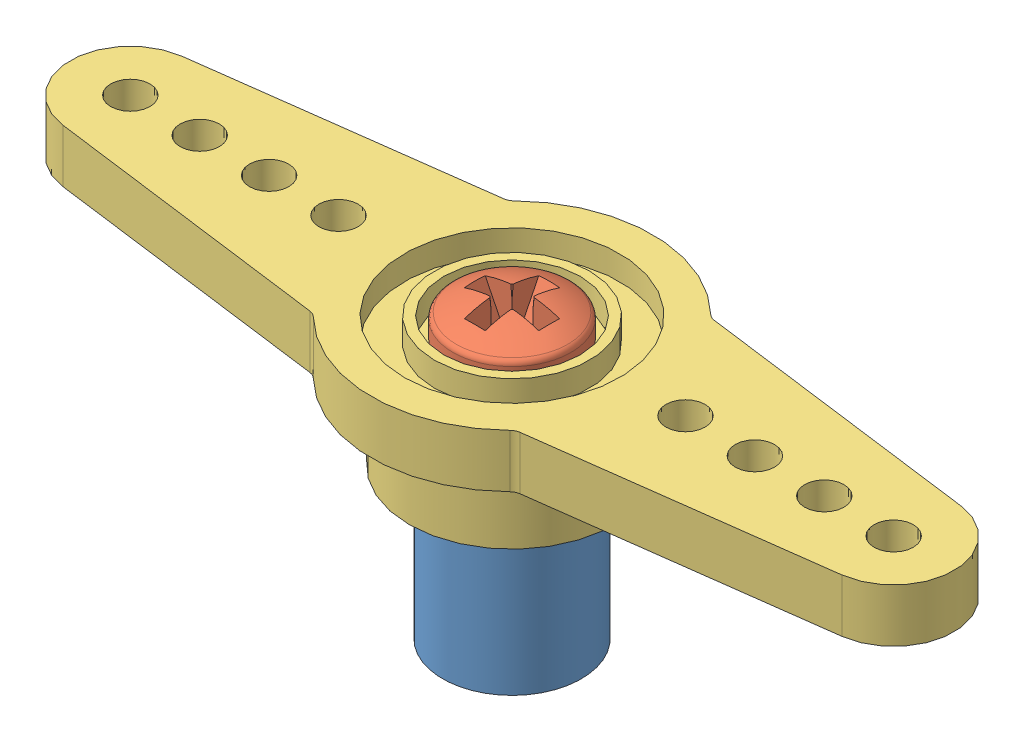
SolidWorks assembly FS5109M_Ensemble arbre, configuration 2S. Lengths in mm.
Overall size (55.74 14.3 36.6).
7 component instances, 7 part files, 23 mates.
Components (placement in the parent):
- FS5109M_arbre-1: FS5109M_arbre [Défaut] at origin size (6 10 6)
- FS5109M_vis arbre M3 x 6-1: FS5109M_vis arbre M3 x 6 [vis arbre M3 x 6] at (0 47.05 0) x (0 -1 0) z (0 0 1) size (7.75 5.1 5.1)
- FS5109M_palo 2S-1: FS5109M_palo 2S [Défaut] at (0 44.2 0) size (38.2 5.6 12.15)
- FS5109M_palo 2B-1: FS5109M_palo 2B [Défaut] at (0 44.2 0) size (55.74 7.8 13.34) (hidden)
- FS5109M_palo C-1: FS5109M_palo C [Défaut] at (0 44.2 0) size (20.9 5.6 20.9) (hidden)
- FS5109M_palo 4-1: FS5109M_palo 4 [Défaut] at (0 44.2 0) size (36.6 5.6 36.6) (hidden)
- FS5109M_palo 6-1: FS5109M_palo 6 [Défaut] at (0 44.2 0) size (31.74 5.6 28.12) (hidden)
Mates (geometry in assembly coordinates):
- Coïncidente1: coordinate: point of FS5109M_arbre-1; point of assembly
- Coaxiale1: concentric aligned: cylinder of FS5109M_arbre-1 through (0 44.2 0) axis (0 1 0) radius 1.25; cylinder of FS5109M_vis arbre M3 x 6-1 through (0 72.45 0) axis (0 1 0) radius 1.5
- Coïncidente2: coincident aligned: line of FS5109M_arbre-1 through (0 0 0) axis (0 1 0); line of FS5109M_palo 2S-1 through (0 44.2 0) axis (0 1 0)
- Coïncidente3: coincident aligned: plane of FS5109M_arbre-1 through (-2.5 44.2 0) normal (0 1 0); plane of FS5109M_palo 2S-1 through (0 44.2 0) normal (0 1 0)
- Coïncidente4: coincident anti-aligned: plane of FS5109M_vis arbre M3 x 6-1 through (1.5 45.25 0) normal (0 -1 0); plane of FS5109M_palo 2S-1 through (0 45.25 0) normal (0 1 0)
- Coïncidente5: coincident aligned: plane of FS5109M_arbre-1 through (0 0 0) normal (0 0 1); plane of FS5109M_palo 2S-1 through (0 44.2 0) normal (0 0 1)
- Coïncidente6: coincident aligned: line of FS5109M_arbre-1 through (0 0 0) axis (0 1 0); line of FS5109M_palo 2B-1 through (0 44.2 0) axis (0 1 0)
- Coïncidente7: coincident aligned: plane of FS5109M_arbre-1 through (0 0 0) normal (0 0 1); plane of FS5109M_palo 2B-1 through (0 44.2 0) normal (0 0 1)
- Coïncidente8: coincident aligned: plane of FS5109M_arbre-1 through (-2.5 44.2 0) normal (0 1 0); plane of FS5109M_palo 2B-1 through (0 44.2 0) normal (0 1 0)
- Coïncidente9: coincident anti-aligned: plane of FS5109M_vis arbre M3 x 6-1 through (0.732 45.2 1.3093) normal (0 -1 0); plane of FS5109M_palo 2B-1 through (0 45.2 0) normal (0 1 0)
- Coïncidente10: coincident anti-aligned: plane of FS5109M_vis arbre M3 x 6-1 through (0.732 45.25 1.3093) normal (0 -1 0); plane of FS5109M_palo C-1 through (0 45.25 0) normal (0 1 0)
- Coïncidente11: coincident aligned: plane of FS5109M_arbre-1 through (-2.5 44.2 0) normal (0 1 0); plane of FS5109M_palo C-1 through (0 44.2 0) normal (0 1 0)
- Coïncidente12: coincident aligned: line of FS5109M_arbre-1 through (0 0 0) axis (0 1 0); line of FS5109M_palo C-1 through (0 44.2 0) axis (0 1 0)
- Coïncidente13: coincident aligned: plane of FS5109M_arbre-1 through (0 0 0) normal (0 0 1); plane of FS5109M_palo C-1 through (0 44.2 0) normal (0 0 1)
- Coïncidente14: coincident aligned: line of FS5109M_arbre-1 through (0 0 0) axis (0 1 0); line of FS5109M_palo 4-1 through (0 44.2 0) axis (0 1 0)
- Coïncidente15: coincident aligned: plane of FS5109M_arbre-1 through (-2.5 44.2 0) normal (0 1 0); plane of FS5109M_palo 4-1 through (0 44.2 0) normal (0 1 0)
- Coïncidente17: coincident aligned: plane of FS5109M_arbre-1 through (0 0 0) normal (0 0 1); plane of FS5109M_palo 4-1 through (0 44.2 0) normal (0 0 1)
- Coïncidente18: coincident anti-aligned: plane of FS5109M_vis arbre M3 x 6-1 through (0.6604 45.25 1.3468) normal (0 -1 0); plane of FS5109M_palo 4-1 through (0 45.25 0) normal (0 1 0)
- Coïncidente19: coincident aligned: line of FS5109M_arbre-1 through (0 0 0) axis (0 1 0); line of FS5109M_palo 6-1 through (0 44.2 0) axis (0 1 0)
- Coïncidente20: coincident aligned: plane of FS5109M_arbre-1 through (0 0 0) normal (0 0 1); plane of FS5109M_palo 6-1 through (0 44.2 0) normal (0 0 1)
- Coïncidente21: coincident aligned: plane of FS5109M_arbre-1 through (-2.5 44.2 0) normal (0 1 0); plane of FS5109M_palo 6-1 through (0 44.2 0) normal (0 1 0)
- Coïncidente22: coincident anti-aligned: plane of FS5109M_vis arbre M3 x 6-1 through (0.5667 45.25 1.3888) normal (0 -1 0); plane of FS5109M_palo 6-1 through (0 45.25 0) normal (0 1 0)
- Coïncidente23: coincident aligned: plane of FS5109M_vis arbre M3 x 6-1 through (0 47.05 0) normal (0 0 1); plane of assembly through (0 0 0) normal (0 0 1)
